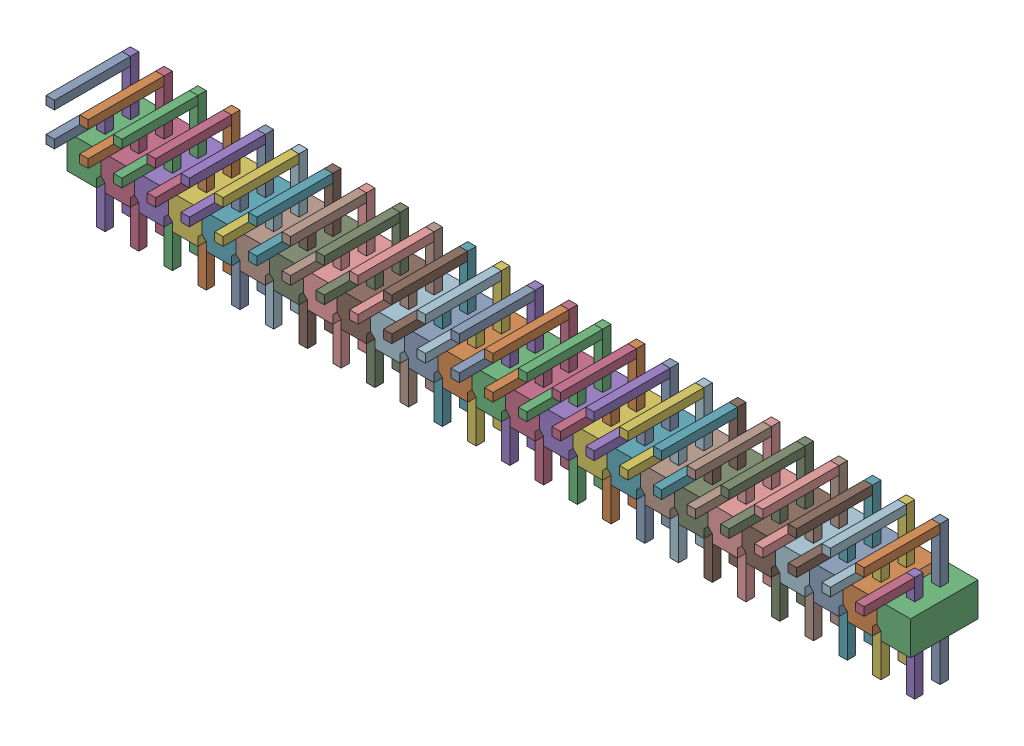
SolidWorks assembly CN301, configuration ﾃﾞﾌｫﾙﾄ. Lengths in mm.
Overall size (50 8.25 6).
250 component instances, 7 part files, 0 mates.
Components (placement in the parent):
- 689263280-1: 689263280 [ﾃﾞﾌｫﾙﾄ] at (17.4999 7.3001 -2.2003) size (0.5 0.5 3)
  - Extruded_10-1: Extruded_10 [ﾃﾞﾌｫﾙﾄ] at origin size (0.5 0.5 3)
- 689263280-2: 689263280 [ﾃﾞﾌｫﾙﾄ] at (19.4999 7.3001 -2.2003) size (0.5 0.5 3)
  - Extruded_10-1: Extruded_10 [ﾃﾞﾌｫﾙﾄ] at origin size (0.5 0.5 3)
- 689263280-3: 689263280 [ﾃﾞﾌｫﾙﾄ] at (21.4999 7.3001 -2.2003) size (0.5 0.5 3)
  - Extruded_10-1: Extruded_10 [ﾃﾞﾌｫﾙﾄ] at origin size (0.5 0.5 3)
- 689263280-4: 689263280 [ﾃﾞﾌｫﾙﾄ] at (23.4999 7.3001 -2.2003) size (0.5 0.5 3)
  - Extruded_10-1: Extruded_10 [ﾃﾞﾌｫﾙﾄ] at origin size (0.5 0.5 3)
- 689263280-5: 689263280 [ﾃﾞﾌｫﾙﾄ] at (25.4999 7.3001 -2.2003) size (0.5 0.5 3)
  - Extruded_10-1: Extruded_10 [ﾃﾞﾌｫﾙﾄ] at origin size (0.5 0.5 3)
- 689263280-6: 689263280 [ﾃﾞﾌｫﾙﾄ] at (27.4999 7.3001 -2.2003) size (0.5 0.5 3)
  - Extruded_10-1: Extruded_10 [ﾃﾞﾌｫﾙﾄ] at origin size (0.5 0.5 3)
- 689263280-7: 689263280 [ﾃﾞﾌｫﾙﾄ] at (29.4999 7.3001 -2.2003) size (0.5 0.5 3)
  - Extruded_10-1: Extruded_10 [ﾃﾞﾌｫﾙﾄ] at origin size (0.5 0.5 3)
- 689263280-8: 689263280 [ﾃﾞﾌｫﾙﾄ] at (31.4999 7.3001 -2.2003) size (0.5 0.5 3)
  - Extruded_10-1: Extruded_10 [ﾃﾞﾌｫﾙﾄ] at origin size (0.5 0.5 3)
- 689263280-9: 689263280 [ﾃﾞﾌｫﾙﾄ] at (33.4999 7.3001 -2.2003) size (0.5 0.5 3)
  - Extruded_10-1: Extruded_10 [ﾃﾞﾌｫﾙﾄ] at origin size (0.5 0.5 3)
- 689263280-10: 689263280 [ﾃﾞﾌｫﾙﾄ] at (35.4999 7.3001 -2.2003) size (0.5 0.5 3)
  - Extruded_10-1: Extruded_10 [ﾃﾞﾌｫﾙﾄ] at origin size (0.5 0.5 3)
- 689263280-11: 689263280 [ﾃﾞﾌｫﾙﾄ] at (37.4999 7.3001 -2.2003) size (0.5 0.5 3)
  - Extruded_10-1: Extruded_10 [ﾃﾞﾌｫﾙﾄ] at origin size (0.5 0.5 3)
- 689263280-12: 689263280 [ﾃﾞﾌｫﾙﾄ] at (39.4999 7.3001 -2.2003) size (0.5 0.5 3)
  - Extruded_10-1: Extruded_10 [ﾃﾞﾌｫﾙﾄ] at origin size (0.5 0.5 3)
- 689263280-13: 689263280 [ﾃﾞﾌｫﾙﾄ] at (41.4999 7.3001 -2.2003) size (0.5 0.5 3)
  - Extruded_10-1: Extruded_10 [ﾃﾞﾌｫﾙﾄ] at origin size (0.5 0.5 3)
- 689263280-14: 689263280 [ﾃﾞﾌｫﾙﾄ] at (43.4999 7.3001 -2.2003) size (0.5 0.5 3)
  - Extruded_10-1: Extruded_10 [ﾃﾞﾌｫﾙﾄ] at origin size (0.5 0.5 3)
- 689263280-15: 689263280 [ﾃﾞﾌｫﾙﾄ] at (45.4999 7.3001 -2.2003) size (0.5 0.5 3)
  - Extruded_10-1: Extruded_10 [ﾃﾞﾌｫﾙﾄ] at origin size (0.5 0.5 3)
- 689263280-16: 689263280 [ﾃﾞﾌｫﾙﾄ] at (47.4999 7.3001 -2.2003) size (0.5 0.5 3)
  - Extruded_10-1: Extruded_10 [ﾃﾞﾌｫﾙﾄ] at origin size (0.5 0.5 3)
- 689263280-17: 689263280 [ﾃﾞﾌｫﾙﾄ] at (49.4999 7.3001 -2.2003) size (0.5 0.5 3)
  - Extruded_10-1: Extruded_10 [ﾃﾞﾌｫﾙﾄ] at origin size (0.5 0.5 3)
- 689263280-18: 689263280 [ﾃﾞﾌｫﾙﾄ] at (51.4999 7.3001 -2.2003) size (0.5 0.5 3)
  - Extruded_10-1: Extruded_10 [ﾃﾞﾌｫﾙﾄ] at origin size (0.5 0.5 3)
- 689263280-19: 689263280 [ﾃﾞﾌｫﾙﾄ] at (53.4999 7.3001 -2.2003) size (0.5 0.5 3)
  - Extruded_10-1: Extruded_10 [ﾃﾞﾌｫﾙﾄ] at origin size (0.5 0.5 3)
- 689263280-20: 689263280 [ﾃﾞﾌｫﾙﾄ] at (55.4999 7.3001 -2.2003) size (0.5 0.5 3)
  - Extruded_10-1: Extruded_10 [ﾃﾞﾌｫﾙﾄ] at origin size (0.5 0.5 3)
- 689263280-21: 689263280 [ﾃﾞﾌｫﾙﾄ] at (57.4999 7.3001 -2.2003) size (0.5 0.5 3)
  - Extruded_10-1: Extruded_10 [ﾃﾞﾌｫﾙﾄ] at origin size (0.5 0.5 3)
- 689263280-22: 689263280 [ﾃﾞﾌｫﾙﾄ] at (59.4999 7.3001 -2.2003) size (0.5 0.5 3)
  - Extruded_10-1: Extruded_10 [ﾃﾞﾌｫﾙﾄ] at origin size (0.5 0.5 3)
- 689263280-23: 689263280 [ﾃﾞﾌｫﾙﾄ] at (61.4999 7.3001 -2.2003) size (0.5 0.5 3)
  - Extruded_10-1: Extruded_10 [ﾃﾞﾌｫﾙﾄ] at origin size (0.5 0.5 3)
- 689263280-24: 689263280 [ﾃﾞﾌｫﾙﾄ] at (63.4999 7.3001 -2.2003) size (0.5 0.5 3)
  - Extruded_10-1: Extruded_10 [ﾃﾞﾌｫﾙﾄ] at origin size (0.5 0.5 3)
- 689263416-1: 689263416 [ﾃﾞﾌｫﾙﾄ] at (17.5 9.3001 -3.7003) size (0.5 0.5 4.5)
  - Extruded_11-1: Extruded_11 [ﾃﾞﾌｫﾙﾄ] at origin size (0.5 0.5 4.5)
- 689263416-2: 689263416 [ﾃﾞﾌｫﾙﾄ] at (19.5 9.3001 -3.7003) size (0.5 0.5 4.5)
  - Extruded_11-1: Extruded_11 [ﾃﾞﾌｫﾙﾄ] at origin size (0.5 0.5 4.5)
- 689263416-3: 689263416 [ﾃﾞﾌｫﾙﾄ] at (21.5 9.3001 -3.7003) size (0.5 0.5 4.5)
  - Extruded_11-1: Extruded_11 [ﾃﾞﾌｫﾙﾄ] at origin size (0.5 0.5 4.5)
- 689263416-4: 689263416 [ﾃﾞﾌｫﾙﾄ] at (23.5 9.3001 -3.7003) size (0.5 0.5 4.5)
  - Extruded_11-1: Extruded_11 [ﾃﾞﾌｫﾙﾄ] at origin size (0.5 0.5 4.5)
- 689263416-5: 689263416 [ﾃﾞﾌｫﾙﾄ] at (25.5 9.3001 -3.7003) size (0.5 0.5 4.5)
  - Extruded_11-1: Extruded_11 [ﾃﾞﾌｫﾙﾄ] at origin size (0.5 0.5 4.5)
- 689263416-6: 689263416 [ﾃﾞﾌｫﾙﾄ] at (27.5 9.3001 -3.7003) size (0.5 0.5 4.5)
  - Extruded_11-1: Extruded_11 [ﾃﾞﾌｫﾙﾄ] at origin size (0.5 0.5 4.5)
- 689263416-7: 689263416 [ﾃﾞﾌｫﾙﾄ] at (29.5 9.3001 -3.7003) size (0.5 0.5 4.5)
  - Extruded_11-1: Extruded_11 [ﾃﾞﾌｫﾙﾄ] at origin size (0.5 0.5 4.5)
- 689263416-8: 689263416 [ﾃﾞﾌｫﾙﾄ] at (31.5 9.3001 -3.7003) size (0.5 0.5 4.5)
  - Extruded_11-1: Extruded_11 [ﾃﾞﾌｫﾙﾄ] at origin size (0.5 0.5 4.5)
- 689263416-9: 689263416 [ﾃﾞﾌｫﾙﾄ] at (33.5 9.3001 -3.7003) size (0.5 0.5 4.5)
  - Extruded_11-1: Extruded_11 [ﾃﾞﾌｫﾙﾄ] at origin size (0.5 0.5 4.5)
- 689263416-10: 689263416 [ﾃﾞﾌｫﾙﾄ] at (35.5 9.3001 -3.7003) size (0.5 0.5 4.5)
  - Extruded_11-1: Extruded_11 [ﾃﾞﾌｫﾙﾄ] at origin size (0.5 0.5 4.5)
- 689263416-11: 689263416 [ﾃﾞﾌｫﾙﾄ] at (37.5 9.3001 -3.7003) size (0.5 0.5 4.5)
  - Extruded_11-1: Extruded_11 [ﾃﾞﾌｫﾙﾄ] at origin size (0.5 0.5 4.5)
- 689263416-12: 689263416 [ﾃﾞﾌｫﾙﾄ] at (39.5 9.3001 -3.7003) size (0.5 0.5 4.5)
  - Extruded_11-1: Extruded_11 [ﾃﾞﾌｫﾙﾄ] at origin size (0.5 0.5 4.5)
- 689263416-13: 689263416 [ﾃﾞﾌｫﾙﾄ] at (41.5 9.3001 -3.7003) size (0.5 0.5 4.5)
  - Extruded_11-1: Extruded_11 [ﾃﾞﾌｫﾙﾄ] at origin size (0.5 0.5 4.5)
- 689263416-14: 689263416 [ﾃﾞﾌｫﾙﾄ] at (43.5 9.3001 -3.7003) size (0.5 0.5 4.5)
  - Extruded_11-1: Extruded_11 [ﾃﾞﾌｫﾙﾄ] at origin size (0.5 0.5 4.5)
- 689263416-15: 689263416 [ﾃﾞﾌｫﾙﾄ] at (45.5 9.3001 -3.7003) size (0.5 0.5 4.5)
  - Extruded_11-1: Extruded_11 [ﾃﾞﾌｫﾙﾄ] at origin size (0.5 0.5 4.5)
- 689263416-16: 689263416 [ﾃﾞﾌｫﾙﾄ] at (47.5 9.3001 -3.7003) size (0.5 0.5 4.5)
  - Extruded_11-1: Extruded_11 [ﾃﾞﾌｫﾙﾄ] at origin size (0.5 0.5 4.5)
- 689263416-17: 689263416 [ﾃﾞﾌｫﾙﾄ] at (49.5 9.3001 -3.7003) size (0.5 0.5 4.5)
  - Extruded_11-1: Extruded_11 [ﾃﾞﾌｫﾙﾄ] at origin size (0.5 0.5 4.5)
- 689263416-18: 689263416 [ﾃﾞﾌｫﾙﾄ] at (51.5 9.3001 -3.7003) size (0.5 0.5 4.5)
  - Extruded_11-1: Extruded_11 [ﾃﾞﾌｫﾙﾄ] at origin size (0.5 0.5 4.5)
- 689263416-19: 689263416 [ﾃﾞﾌｫﾙﾄ] at (53.5 9.3001 -3.7003) size (0.5 0.5 4.5)
  - Extruded_11-1: Extruded_11 [ﾃﾞﾌｫﾙﾄ] at origin size (0.5 0.5 4.5)
- 689263416-20: 689263416 [ﾃﾞﾌｫﾙﾄ] at (55.5 9.3001 -3.7003) size (0.5 0.5 4.5)
  - Extruded_11-1: Extruded_11 [ﾃﾞﾌｫﾙﾄ] at origin size (0.5 0.5 4.5)
- 689263416-21: 689263416 [ﾃﾞﾌｫﾙﾄ] at (57.5 9.3001 -3.7003) size (0.5 0.5 4.5)
  - Extruded_11-1: Extruded_11 [ﾃﾞﾌｫﾙﾄ] at origin size (0.5 0.5 4.5)
- 689263416-22: 689263416 [ﾃﾞﾌｫﾙﾄ] at (59.5 9.3001 -3.7003) size (0.5 0.5 4.5)
  - Extruded_11-1: Extruded_11 [ﾃﾞﾌｫﾙﾄ] at origin size (0.5 0.5 4.5)
- 689263416-23: 689263416 [ﾃﾞﾌｫﾙﾄ] at (61.5 9.3001 -3.7003) size (0.5 0.5 4.5)
  - Extruded_11-1: Extruded_11 [ﾃﾞﾌｫﾙﾄ] at origin size (0.5 0.5 4.5)
- 689263416-24: 689263416 [ﾃﾞﾌｫﾙﾄ] at (63.5 9.3001 -3.7003) size (0.5 0.5 4.5)
  - Extruded_11-1: Extruded_11 [ﾃﾞﾌｫﾙﾄ] at origin size (0.5 0.5 4.5)
- 689263552-1: 689263552 [ﾃﾞﾌｫﾙﾄ] at (65.4999 5.425 -4.2003) size (0.5 8.25 0.5)
  - Extruded_12-1: Extruded_12 [ﾃﾞﾌｫﾙﾄ] at origin size (0.5 8.25 0.5)
- 689263416-25: 689263416 [ﾃﾞﾌｫﾙﾄ] at (65.4999 9.3001 -3.7003) size (0.5 0.5 4.5)
  - Extruded_11-1: Extruded_11 [ﾃﾞﾌｫﾙﾄ] at origin size (0.5 0.5 4.5)
- 689263688-1: 689263688 [ﾃﾞﾌｫﾙﾄ] at (17.5 5.3 -5.2003) size (2 2 4)
  - Extruded_13-1: Extruded_13 [ﾃﾞﾌｫﾙﾄ] at origin size (2 2 4)
- 689263824-1: 689263824 [ﾃﾞﾌｫﾙﾄ] at (19.5 5.3 -5.2003) size (2 2 4)
  - Extruded_14-1: Extruded_14 [ﾃﾞﾌｫﾙﾄ] at origin size (2 2 4)
- 689263824-2: 689263824 [ﾃﾞﾌｫﾙﾄ] at (21.5 5.3 -5.2003) size (2 2 4)
  - Extruded_14-1: Extruded_14 [ﾃﾞﾌｫﾙﾄ] at origin size (2 2 4)
- 689263824-3: 689263824 [ﾃﾞﾌｫﾙﾄ] at (23.5 5.3 -5.2003) size (2 2 4)
  - Extruded_14-1: Extruded_14 [ﾃﾞﾌｫﾙﾄ] at origin size (2 2 4)
- 689263824-4: 689263824 [ﾃﾞﾌｫﾙﾄ] at (25.5 5.3 -5.2003) size (2 2 4)
  - Extruded_14-1: Extruded_14 [ﾃﾞﾌｫﾙﾄ] at origin size (2 2 4)
- 689263824-5: 689263824 [ﾃﾞﾌｫﾙﾄ] at (27.5 5.3 -5.2003) size (2 2 4)
  - Extruded_14-1: Extruded_14 [ﾃﾞﾌｫﾙﾄ] at origin size (2 2 4)
- 689263824-6: 689263824 [ﾃﾞﾌｫﾙﾄ] at (29.5 5.3 -5.2003) size (2 2 4)
  - Extruded_14-1: Extruded_14 [ﾃﾞﾌｫﾙﾄ] at origin size (2 2 4)
- 689263824-7: 689263824 [ﾃﾞﾌｫﾙﾄ] at (31.5 5.3 -5.2003) size (2 2 4)
  - Extruded_14-1: Extruded_14 [ﾃﾞﾌｫﾙﾄ] at origin size (2 2 4)
- 689263824-8: 689263824 [ﾃﾞﾌｫﾙﾄ] at (33.5 5.3 -5.2003) size (2 2 4)
  - Extruded_14-1: Extruded_14 [ﾃﾞﾌｫﾙﾄ] at origin size (2 2 4)
- 689263824-9: 689263824 [ﾃﾞﾌｫﾙﾄ] at (35.5 5.3 -5.2003) size (2 2 4)
  - Extruded_14-1: Extruded_14 [ﾃﾞﾌｫﾙﾄ] at origin size (2 2 4)
- 689263824-10: 689263824 [ﾃﾞﾌｫﾙﾄ] at (37.5 5.3 -5.2003) size (2 2 4)
  - Extruded_14-1: Extruded_14 [ﾃﾞﾌｫﾙﾄ] at origin size (2 2 4)
- 689263824-11: 689263824 [ﾃﾞﾌｫﾙﾄ] at (39.5 5.3 -5.2003) size (2 2 4)
  - Extruded_14-1: Extruded_14 [ﾃﾞﾌｫﾙﾄ] at origin size (2 2 4)
- 689263824-12: 689263824 [ﾃﾞﾌｫﾙﾄ] at (41.5 5.3 -5.2003) size (2 2 4)
  - Extruded_14-1: Extruded_14 [ﾃﾞﾌｫﾙﾄ] at origin size (2 2 4)
- 689263824-13: 689263824 [ﾃﾞﾌｫﾙﾄ] at (43.5 5.3 -5.2003) size (2 2 4)
  - Extruded_14-1: Extruded_14 [ﾃﾞﾌｫﾙﾄ] at origin size (2 2 4)
- 689263824-14: 689263824 [ﾃﾞﾌｫﾙﾄ] at (45.5 5.3 -5.2003) size (2 2 4)
  - Extruded_14-1: Extruded_14 [ﾃﾞﾌｫﾙﾄ] at origin size (2 2 4)
- 689263824-15: 689263824 [ﾃﾞﾌｫﾙﾄ] at (47.5 5.3 -5.2003) size (2 2 4)
  - Extruded_14-1: Extruded_14 [ﾃﾞﾌｫﾙﾄ] at origin size (2 2 4)
- 689263824-16: 689263824 [ﾃﾞﾌｫﾙﾄ] at (49.5 5.3 -5.2003) size (2 2 4)
  - Extruded_14-1: Extruded_14 [ﾃﾞﾌｫﾙﾄ] at origin size (2 2 4)
- 689263824-17: 689263824 [ﾃﾞﾌｫﾙﾄ] at (51.5 5.3 -5.2003) size (2 2 4)
  - Extruded_14-1: Extruded_14 [ﾃﾞﾌｫﾙﾄ] at origin size (2 2 4)
- 689263824-18: 689263824 [ﾃﾞﾌｫﾙﾄ] at (53.5 5.3 -5.2003) size (2 2 4)
  - Extruded_14-1: Extruded_14 [ﾃﾞﾌｫﾙﾄ] at origin size (2 2 4)
- 689263824-19: 689263824 [ﾃﾞﾌｫﾙﾄ] at (55.5 5.3 -5.2003) size (2 2 4)
  - Extruded_14-1: Extruded_14 [ﾃﾞﾌｫﾙﾄ] at origin size (2 2 4)
- 689263824-20: 689263824 [ﾃﾞﾌｫﾙﾄ] at (57.5 5.3 -5.2003) size (2 2 4)
  - Extruded_14-1: Extruded_14 [ﾃﾞﾌｫﾙﾄ] at origin size (2 2 4)
- 689263824-21: 689263824 [ﾃﾞﾌｫﾙﾄ] at (59.5 5.3 -5.2003) size (2 2 4)
  - Extruded_14-1: Extruded_14 [ﾃﾞﾌｫﾙﾄ] at origin size (2 2 4)
- 689263824-22: 689263824 [ﾃﾞﾌｫﾙﾄ] at (61.5 5.3 -5.2003) size (2 2 4)
  - Extruded_14-1: Extruded_14 [ﾃﾞﾌｫﾙﾄ] at origin size (2 2 4)
- 689263824-23: 689263824 [ﾃﾞﾌｫﾙﾄ] at (63.5 5.3 -5.2003) size (2 2 4)
  - Extruded_14-1: Extruded_14 [ﾃﾞﾌｫﾙﾄ] at origin size (2 2 4)
- 689263960-1: 689263960 [ﾃﾞﾌｫﾙﾄ] at (65.5 5.3 -5.2003) size (2 2 4)
  - Extruded_15-1: Extruded_15 [ﾃﾞﾌｫﾙﾄ] at origin size (2 2 4)
- 689263280-25: 689263280 [ﾃﾞﾌｫﾙﾄ] at (65.4999 7.3001 -2.2003) size (0.5 0.5 3)
  - Extruded_10-1: Extruded_10 [ﾃﾞﾌｫﾙﾄ] at origin size (0.5 0.5 3)
- 689264096-1: 689264096 [ﾃﾞﾌｫﾙﾄ] at (65.4999 4.425 -2.7003) size (0.5 6.25 0.5)
  - Extruded_16-1: Extruded_16 [ﾃﾞﾌｫﾙﾄ] at origin size (0.5 6.25 0.5)
- 689264096-2: 689264096 [ﾃﾞﾌｫﾙﾄ] at (63.4999 4.425 -2.7003) size (0.5 6.25 0.5)
  - Extruded_16-1: Extruded_16 [ﾃﾞﾌｫﾙﾄ] at origin size (0.5 6.25 0.5)
- 689264096-3: 689264096 [ﾃﾞﾌｫﾙﾄ] at (61.4999 4.425 -2.7003) size (0.5 6.25 0.5)
  - Extruded_16-1: Extruded_16 [ﾃﾞﾌｫﾙﾄ] at origin size (0.5 6.25 0.5)
- 689264096-4: 689264096 [ﾃﾞﾌｫﾙﾄ] at (59.4999 4.425 -2.7003) size (0.5 6.25 0.5)
  - Extruded_16-1: Extruded_16 [ﾃﾞﾌｫﾙﾄ] at origin size (0.5 6.25 0.5)
- 689264096-5: 689264096 [ﾃﾞﾌｫﾙﾄ] at (57.4999 4.425 -2.7003) size (0.5 6.25 0.5)
  - Extruded_16-1: Extruded_16 [ﾃﾞﾌｫﾙﾄ] at origin size (0.5 6.25 0.5)
- 689264096-6: 689264096 [ﾃﾞﾌｫﾙﾄ] at (55.4999 4.425 -2.7003) size (0.5 6.25 0.5)
  - Extruded_16-1: Extruded_16 [ﾃﾞﾌｫﾙﾄ] at origin size (0.5 6.25 0.5)
- 689264096-7: 689264096 [ﾃﾞﾌｫﾙﾄ] at (53.4999 4.425 -2.7003) size (0.5 6.25 0.5)
  - Extruded_16-1: Extruded_16 [ﾃﾞﾌｫﾙﾄ] at origin size (0.5 6.25 0.5)
- 689264096-8: 689264096 [ﾃﾞﾌｫﾙﾄ] at (51.4999 4.425 -2.7003) size (0.5 6.25 0.5)
  - Extruded_16-1: Extruded_16 [ﾃﾞﾌｫﾙﾄ] at origin size (0.5 6.25 0.5)
- 689264096-9: 689264096 [ﾃﾞﾌｫﾙﾄ] at (49.4999 4.425 -2.7003) size (0.5 6.25 0.5)
  - Extruded_16-1: Extruded_16 [ﾃﾞﾌｫﾙﾄ] at origin size (0.5 6.25 0.5)
- 689264096-10: 689264096 [ﾃﾞﾌｫﾙﾄ] at (47.4999 4.425 -2.7003) size (0.5 6.25 0.5)
  - Extruded_16-1: Extruded_16 [ﾃﾞﾌｫﾙﾄ] at origin size (0.5 6.25 0.5)
- 689264096-11: 689264096 [ﾃﾞﾌｫﾙﾄ] at (45.4999 4.425 -2.7003) size (0.5 6.25 0.5)
  - Extruded_16-1: Extruded_16 [ﾃﾞﾌｫﾙﾄ] at origin size (0.5 6.25 0.5)
- 689264096-12: 689264096 [ﾃﾞﾌｫﾙﾄ] at (43.4999 4.425 -2.7003) size (0.5 6.25 0.5)
  - Extruded_16-1: Extruded_16 [ﾃﾞﾌｫﾙﾄ] at origin size (0.5 6.25 0.5)
- 689264096-13: 689264096 [ﾃﾞﾌｫﾙﾄ] at (41.4999 4.425 -2.7003) size (0.5 6.25 0.5)
  - Extruded_16-1: Extruded_16 [ﾃﾞﾌｫﾙﾄ] at origin size (0.5 6.25 0.5)
- 689264096-14: 689264096 [ﾃﾞﾌｫﾙﾄ] at (39.4999 4.425 -2.7003) size (0.5 6.25 0.5)
  - Extruded_16-1: Extruded_16 [ﾃﾞﾌｫﾙﾄ] at origin size (0.5 6.25 0.5)
- 689264096-15: 689264096 [ﾃﾞﾌｫﾙﾄ] at (37.4999 4.425 -2.7003) size (0.5 6.25 0.5)
  - Extruded_16-1: Extruded_16 [ﾃﾞﾌｫﾙﾄ] at origin size (0.5 6.25 0.5)
- 689264096-16: 689264096 [ﾃﾞﾌｫﾙﾄ] at (35.4999 4.425 -2.7003) size (0.5 6.25 0.5)
  - Extruded_16-1: Extruded_16 [ﾃﾞﾌｫﾙﾄ] at origin size (0.5 6.25 0.5)
- 689264096-17: 689264096 [ﾃﾞﾌｫﾙﾄ] at (33.4999 4.425 -2.7003) size (0.5 6.25 0.5)
  - Extruded_16-1: Extruded_16 [ﾃﾞﾌｫﾙﾄ] at origin size (0.5 6.25 0.5)
- 689264096-18: 689264096 [ﾃﾞﾌｫﾙﾄ] at (31.4999 4.425 -2.7003) size (0.5 6.25 0.5)
  - Extruded_16-1: Extruded_16 [ﾃﾞﾌｫﾙﾄ] at origin size (0.5 6.25 0.5)
- 689264096-19: 689264096 [ﾃﾞﾌｫﾙﾄ] at (29.4999 4.425 -2.7003) size (0.5 6.25 0.5)
  - Extruded_16-1: Extruded_16 [ﾃﾞﾌｫﾙﾄ] at origin size (0.5 6.25 0.5)
- 689264096-20: 689264096 [ﾃﾞﾌｫﾙﾄ] at (27.4999 4.425 -2.7003) size (0.5 6.25 0.5)
  - Extruded_16-1: Extruded_16 [ﾃﾞﾌｫﾙﾄ] at origin size (0.5 6.25 0.5)
- 689264096-21: 689264096 [ﾃﾞﾌｫﾙﾄ] at (25.4999 4.425 -2.7003) size (0.5 6.25 0.5)
  - Extruded_16-1: Extruded_16 [ﾃﾞﾌｫﾙﾄ] at origin size (0.5 6.25 0.5)
- 689264096-22: 689264096 [ﾃﾞﾌｫﾙﾄ] at (23.4999 4.425 -2.7003) size (0.5 6.25 0.5)
  - Extruded_16-1: Extruded_16 [ﾃﾞﾌｫﾙﾄ] at origin size (0.5 6.25 0.5)
- 689264096-23: 689264096 [ﾃﾞﾌｫﾙﾄ] at (21.4999 4.425 -2.7003) size (0.5 6.25 0.5)
  - Extruded_16-1: Extruded_16 [ﾃﾞﾌｫﾙﾄ] at origin size (0.5 6.25 0.5)
- 689264096-24: 689264096 [ﾃﾞﾌｫﾙﾄ] at (19.4999 4.425 -2.7003) size (0.5 6.25 0.5)
  - Extruded_16-1: Extruded_16 [ﾃﾞﾌｫﾙﾄ] at origin size (0.5 6.25 0.5)
- 689264096-25: 689264096 [ﾃﾞﾌｫﾙﾄ] at (17.4999 4.425 -2.7003) size (0.5 6.25 0.5)
  - Extruded_16-1: Extruded_16 [ﾃﾞﾌｫﾙﾄ] at origin size (0.5 6.25 0.5)
- 689263552-2: 689263552 [ﾃﾞﾌｫﾙﾄ] at (63.4999 5.425 -4.2003) size (0.5 8.25 0.5)
  - Extruded_12-1: Extruded_12 [ﾃﾞﾌｫﾙﾄ] at origin size (0.5 8.25 0.5)
- 689263552-3: 689263552 [ﾃﾞﾌｫﾙﾄ] at (61.4999 5.425 -4.2003) size (0.5 8.25 0.5)
  - Extruded_12-1: Extruded_12 [ﾃﾞﾌｫﾙﾄ] at origin size (0.5 8.25 0.5)
- 689263552-4: 689263552 [ﾃﾞﾌｫﾙﾄ] at (59.4999 5.425 -4.2003) size (0.5 8.25 0.5)
  - Extruded_12-1: Extruded_12 [ﾃﾞﾌｫﾙﾄ] at origin size (0.5 8.25 0.5)
- 689263552-5: 689263552 [ﾃﾞﾌｫﾙﾄ] at (57.5 5.425 -4.2003) size (0.5 8.25 0.5)
  - Extruded_12-1: Extruded_12 [ﾃﾞﾌｫﾙﾄ] at origin size (0.5 8.25 0.5)
- 689263552-6: 689263552 [ﾃﾞﾌｫﾙﾄ] at (55.4999 5.425 -4.2003) size (0.5 8.25 0.5)
  - Extruded_12-1: Extruded_12 [ﾃﾞﾌｫﾙﾄ] at origin size (0.5 8.25 0.5)
- 689263552-7: 689263552 [ﾃﾞﾌｫﾙﾄ] at (53.4999 5.425 -4.2003) size (0.5 8.25 0.5)
  - Extruded_12-1: Extruded_12 [ﾃﾞﾌｫﾙﾄ] at origin size (0.5 8.25 0.5)
- 689263552-8: 689263552 [ﾃﾞﾌｫﾙﾄ] at (51.4999 5.425 -4.2003) size (0.5 8.25 0.5)
  - Extruded_12-1: Extruded_12 [ﾃﾞﾌｫﾙﾄ] at origin size (0.5 8.25 0.5)
- 689263552-9: 689263552 [ﾃﾞﾌｫﾙﾄ] at (49.4999 5.425 -4.2003) size (0.5 8.25 0.5)
  - Extruded_12-1: Extruded_12 [ﾃﾞﾌｫﾙﾄ] at origin size (0.5 8.25 0.5)
- 689263552-10: 689263552 [ﾃﾞﾌｫﾙﾄ] at (47.4999 5.425 -4.2003) size (0.5 8.25 0.5)
  - Extruded_12-1: Extruded_12 [ﾃﾞﾌｫﾙﾄ] at origin size (0.5 8.25 0.5)
- 689263552-11: 689263552 [ﾃﾞﾌｫﾙﾄ] at (45.4999 5.425 -4.2003) size (0.5 8.25 0.5)
  - Extruded_12-1: Extruded_12 [ﾃﾞﾌｫﾙﾄ] at origin size (0.5 8.25 0.5)
- 689263552-12: 689263552 [ﾃﾞﾌｫﾙﾄ] at (43.5 5.425 -4.2003) size (0.5 8.25 0.5)
  - Extruded_12-1: Extruded_12 [ﾃﾞﾌｫﾙﾄ] at origin size (0.5 8.25 0.5)
- 689263552-13: 689263552 [ﾃﾞﾌｫﾙﾄ] at (41.4999 5.425 -4.2003) size (0.5 8.25 0.5)
  - Extruded_12-1: Extruded_12 [ﾃﾞﾌｫﾙﾄ] at origin size (0.5 8.25 0.5)
- 689263552-14: 689263552 [ﾃﾞﾌｫﾙﾄ] at (39.4999 5.425 -4.2003) size (0.5 8.25 0.5)
  - Extruded_12-1: Extruded_12 [ﾃﾞﾌｫﾙﾄ] at origin size (0.5 8.25 0.5)
- 689263552-15: 689263552 [ﾃﾞﾌｫﾙﾄ] at (37.4999 5.425 -4.2003) size (0.5 8.25 0.5)
  - Extruded_12-1: Extruded_12 [ﾃﾞﾌｫﾙﾄ] at origin size (0.5 8.25 0.5)
- 689263552-16: 689263552 [ﾃﾞﾌｫﾙﾄ] at (35.4999 5.425 -4.2003) size (0.5 8.25 0.5)
  - Extruded_12-1: Extruded_12 [ﾃﾞﾌｫﾙﾄ] at origin size (0.5 8.25 0.5)
- 689263552-17: 689263552 [ﾃﾞﾌｫﾙﾄ] at (33.4999 5.425 -4.2003) size (0.5 8.25 0.5)
  - Extruded_12-1: Extruded_12 [ﾃﾞﾌｫﾙﾄ] at origin size (0.5 8.25 0.5)
- 689263552-18: 689263552 [ﾃﾞﾌｫﾙﾄ] at (31.4999 5.425 -4.2003) size (0.5 8.25 0.5)
  - Extruded_12-1: Extruded_12 [ﾃﾞﾌｫﾙﾄ] at origin size (0.5 8.25 0.5)
- 689263552-19: 689263552 [ﾃﾞﾌｫﾙﾄ] at (29.5 5.425 -4.2003) size (0.5 8.25 0.5)
  - Extruded_12-1: Extruded_12 [ﾃﾞﾌｫﾙﾄ] at origin size (0.5 8.25 0.5)
- 689263552-20: 689263552 [ﾃﾞﾌｫﾙﾄ] at (27.4999 5.425 -4.2003) size (0.5 8.25 0.5)
  - Extruded_12-1: Extruded_12 [ﾃﾞﾌｫﾙﾄ] at origin size (0.5 8.25 0.5)
- 689263552-21: 689263552 [ﾃﾞﾌｫﾙﾄ] at (25.4999 5.425 -4.2003) size (0.5 8.25 0.5)
  - Extruded_12-1: Extruded_12 [ﾃﾞﾌｫﾙﾄ] at origin size (0.5 8.25 0.5)
- 689263552-22: 689263552 [ﾃﾞﾌｫﾙﾄ] at (23.4999 5.425 -4.2003) size (0.5 8.25 0.5)
  - Extruded_12-1: Extruded_12 [ﾃﾞﾌｫﾙﾄ] at origin size (0.5 8.25 0.5)
- 689263552-23: 689263552 [ﾃﾞﾌｫﾙﾄ] at (21.4999 5.425 -4.2003) size (0.5 8.25 0.5)
  - Extruded_12-1: Extruded_12 [ﾃﾞﾌｫﾙﾄ] at origin size (0.5 8.25 0.5)
- 689263552-24: 689263552 [ﾃﾞﾌｫﾙﾄ] at (19.4999 5.425 -4.2003) size (0.5 8.25 0.5)
  - Extruded_12-1: Extruded_12 [ﾃﾞﾌｫﾙﾄ] at origin size (0.5 8.25 0.5)
- 689263552-25: 689263552 [ﾃﾞﾌｫﾙﾄ] at (17.4999 5.425 -4.2003) size (0.5 8.25 0.5)
  - Extruded_12-1: Extruded_12 [ﾃﾞﾌｫﾙﾄ] at origin size (0.5 8.25 0.5)
